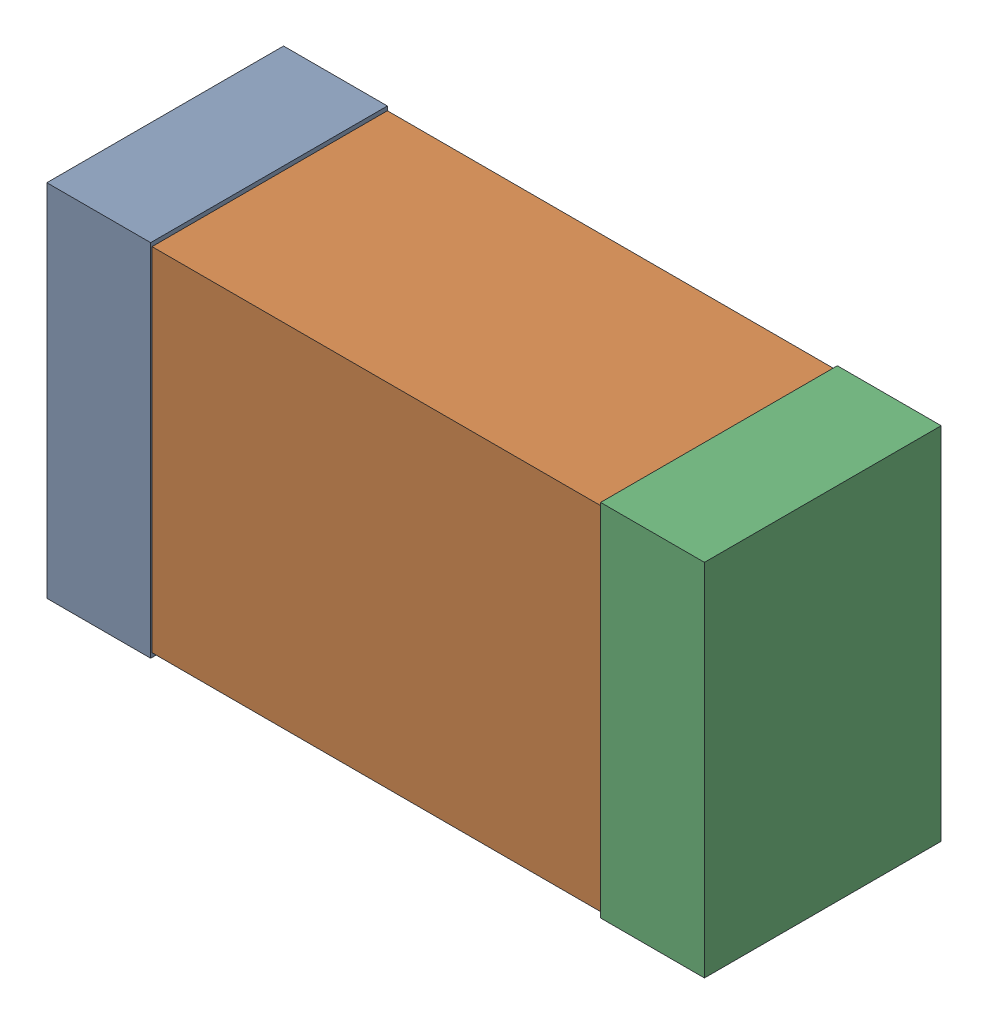
SolidWorks assembly R3_Motor_5Kanaloa_v2.0.0_Motor, configuration Default. Lengths in mm.
Overall size (2.38 1.3 0.85).
6 component instances, 2 part files, 0 mates.
Components (placement in the parent):
- 352877648-1: 352877648 [Default] at (126.821 93.472 0) size (0.38 1.3 0.85)
  - Extruded_14-1: Extruded_14 [Default] at origin size (0.38 1.3 0.85)
- 352877392-1: 352877392 [Default] at (127.821 93.472 0) size (2.2 1.27 0.85)
  - Extruded_15-1: Extruded_15 [Default] at origin size (2.2 1.27 0.85)
- 352877648-2: 352877648 [Default] at (128.821 93.472 0) size (0.38 1.3 0.85)
  - Extruded_14-1: Extruded_14 [Default] at origin size (0.38 1.3 0.85)
